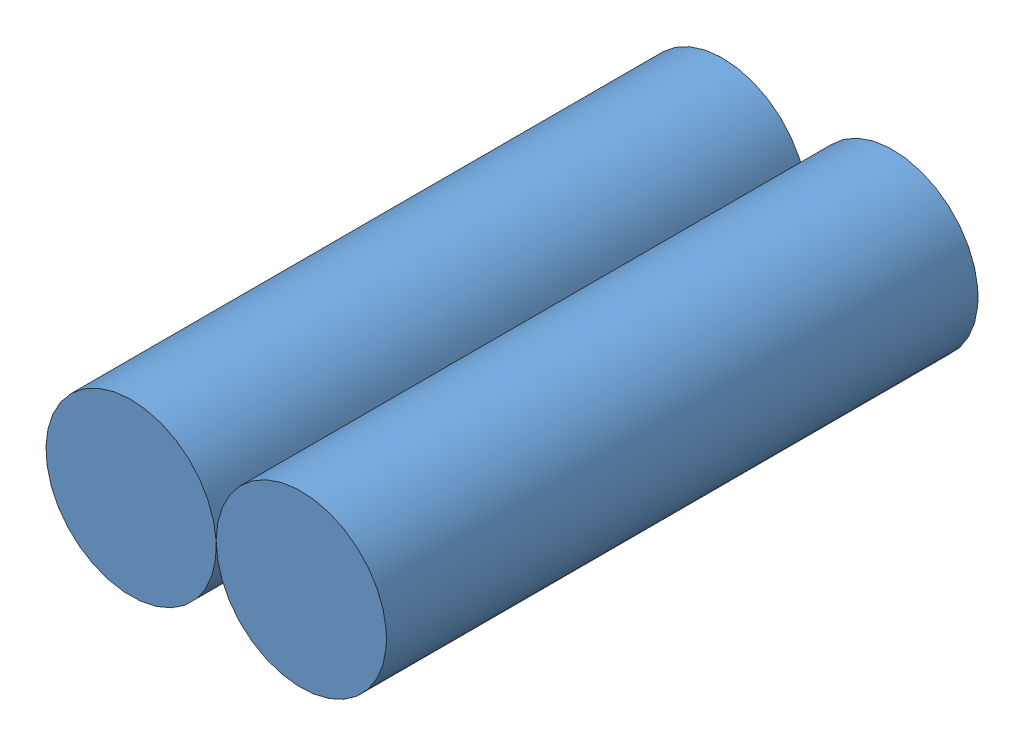
SolidWorks assembly Bateria, configuration Valor predeterminado. Lengths in mm.
Overall size (41.7 26.42 66).
2 component instances, 1 part files, 4 mates.
Components (placement in the parent):
- Célula Bateria-1: Célula Bateria [Valor predeterminado] at (-2.8011 -1.0204 33) size (19 19 66)
- Célula Bateria-2: Célula Bateria [Valor predeterminado] at (-21.7903 -1.6587 33) x (0.824573 -0.565755 0) z (0 0 1) size (19 19 66)
Mates (geometry in assembly coordinates):
- Paralelo1: parallel aligned: plane of Célula Bateria-1 through (-2.8011 -1.0204 99) normal (0 0 1); plane of Célula Bateria-2 through (-21.7903 -1.6587 99) normal (0 0 1)
- Tangente2: tangent anti-aligned: cylinder of Célula Bateria-1 through (-2.8011 -1.0204 99) axis (0 0 -1) radius 9.5; cylinder of Célula Bateria-2 through (-21.7903 -1.6587 99) axis (0 0 -1) radius 9.5
- Coincidente1: coincident aligned: plane of Célula Bateria-1 through (-2.8011 -1.0204 99) normal (0 0 1); plane of Célula Bateria-2 through (-21.7903 -1.6587 99) normal (0 0 1)
- Tangente6: tangent anti-aligned: cylinder of Célula Bateria-2 through (-21.7903 -1.6587 99) axis (0 0 -1) radius 9.5; plane of assembly through (-12.3268 -0.4143 0) normal (-0.999436 -0.033594 0)
